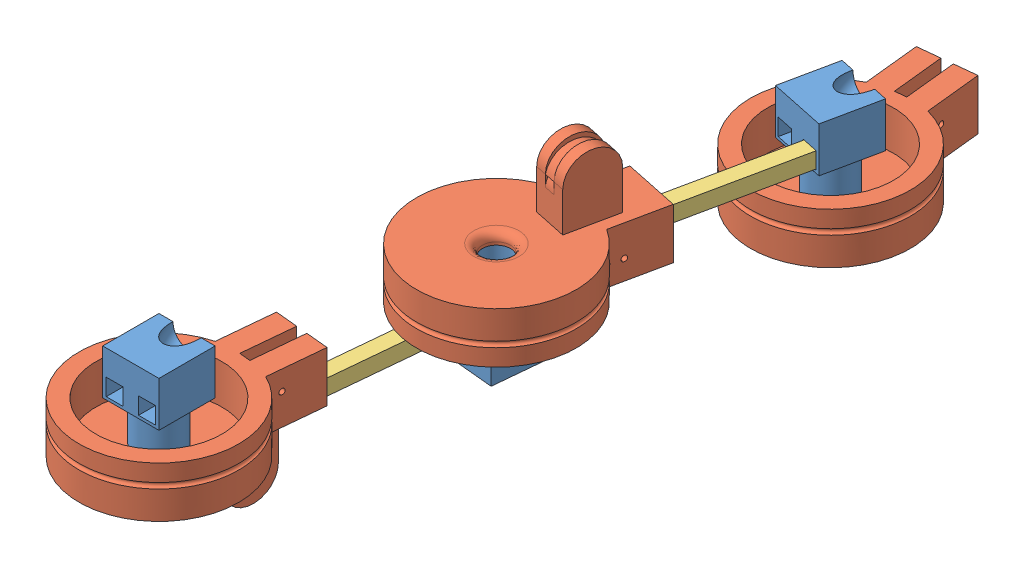
SolidWorks assembly armAssem, configuration Default. Lengths in mm.
Overall size (57.94 36.24 141.57).
8 component instances, 3 part files, 18 mates.
Components (placement in the parent):
- inner2-1: inner2 [Default] at (4.1291 2.2209 19.1305) size (10 17.3 11.09)
- outer2-1: outer2 [Default] at (4.1291 9.2209 19.1305) x (0.094848 0 -0.995492) z (-0.995492 0 -0.094848) size (39.58 20.5 34.24)
- lnik-1: lnik [Default] at (8.6229 2.359 1.1825) x (0 -1 0) z (0.094848 0 -0.995492) size (2.8 2.8 30)
- outer2-2: outer2 [Default] at (14.6147 4.459 -30.3915) x (0.205509 0 -0.978655) z (0.978655 0 0.205509) size (39.58 20.5 34.24)
- inner2-2: inner2 [Default] at (14.6147 11.459 -30.3915) x (-0.995492 0 -0.094848) z (-0.094848 0 0.995492) size (10 17.3 11.09)
- outer2-4: outer2 [Default] at (24.7558 9.2209 -79.6521) x (-0.104197 0 -0.994557) z (-0.994557 0 0.104197) size (39.58 20.5 34.24)
- inner2-4: inner2 [Default] at (24.7558 2.2209 -79.6521) x (0.978655 0 0.205509) z (-0.205509 0 0.978655) size (10 17.3 11.09)
- lnik-3: lnik [Default] at (21.0862 11.3209 -47.7248) x (0 1 0) z (0.205509 0 -0.978655) size (2.8 2.8 30)
Mates (geometry in assembly coordinates):
- Coincident1: coincident anti-aligned: plane of inner2-1 through (4.1291 2.2209 19.1305) normal (0 -1 0); plane of outer2-1 through (4.1291 2.2209 19.1305) normal (0 1 0)
- Coincident2: coincident anti-aligned: circle of inner2-1; circle of outer2-1
- Coincident3: coincident anti-aligned: plane of outer2-1 through (5.8642 9.2209 0.9197) normal (0.094848 0 -0.995492); plane of lnik-1 through (8.6229 2.359 1.1825) normal (-0.094848 0 0.995492)
- Coincident4: coincident anti-aligned: plane of outer2-1 through (7.2292 3.759 1.0498) normal (0 -1 0); plane of lnik-1 through (10.0747 3.759 -28.815) normal (0 1 0)
- Coincident5: coincident anti-aligned: plane of outer2-1 through (7.2292 0.759 1.0498) normal (0.995492 0 0.094848); plane of lnik-1 through (10.0747 3.759 -28.815) normal (-0.995492 0 -0.094848)
- Coincident6: coincident anti-aligned: plane of outer2-2 through (14.6147 11.459 -30.3915) normal (0 -1 0); plane of inner2-2 through (14.6147 11.459 -30.3915) normal (0 1 0)
- Coincident7: coincident anti-aligned: circle of outer2-2; circle of inner2-2
- Coincident17: coincident anti-aligned: plane of lnik-1 through (11.4684 2.359 -28.6822) normal (0.094848 0 -0.995492); plane of inner2-2 through (14.425 11.459 -28.4005) normal (-0.094848 0 0.995492)
- Coincident18: coincident anti-aligned: plane of lnik-1 through (10.0747 0.959 -28.815) normal (0 -1 0); plane of inner2-2 through (13.0611 0.959 -28.5305) normal (0 1 0)
- Coincident19: coincident anti-aligned: plane of lnik-1 through (10.0747 3.759 -28.815) normal (-0.995492 0 -0.094848); plane of inner2-2 through (10.0747 0.959 -28.815) normal (0.995492 0 0.094848)
- Coincident20: coincident anti-aligned: circle of outer2-4; circle of inner2-4
- Coincident21: coincident anti-aligned: plane of outer2-4 through (24.7558 2.2209 -79.6521) normal (0 1 0); plane of inner2-4 through (24.7558 2.2209 -79.6521) normal (0 -1 0)
- Coincident22: coincident anti-aligned: plane of inner2-4 through (24.3448 2.2209 -77.6948) normal (-0.205509 0 0.978655); plane of lnik-3 through (27.2514 11.3209 -77.0844) normal (0.205509 0 -0.978655)
- Coincident23: coincident anti-aligned: plane of inner2-4 through (28.6216 12.7209 -76.7967) normal (-0.978655 0 -0.205509); plane of lnik-3 through (28.6216 9.9209 -76.7967) normal (0.978655 0 0.205509)
- Coincident24: coincident anti-aligned: plane of inner2-4 through (25.6856 12.7209 -77.4132) normal (0 -1 0); plane of lnik-3 through (28.6216 12.7209 -76.7967) normal (0 1 0)
- Coincident25: coincident anti-aligned: plane of outer2-2 through (19.716 9.9209 -48.0125) normal (0 1 0); plane of lnik-3 through (28.6216 9.9209 -76.7967) normal (0 -1 0)
- Coincident26: coincident anti-aligned: plane of outer2-2 through (19.716 12.9209 -48.0125) normal (0.978655 0 0.205509); plane of lnik-3 through (25.8813 9.9209 -77.3721) normal (-0.978655 0 -0.205509)
- Coincident27: coincident anti-aligned: plane of outer2-2 through (18.3741 4.459 -48.2943) normal (0.205509 0 -0.978655); plane of lnik-3 through (21.0862 11.3209 -47.7248) normal (-0.205509 0 0.978655)
